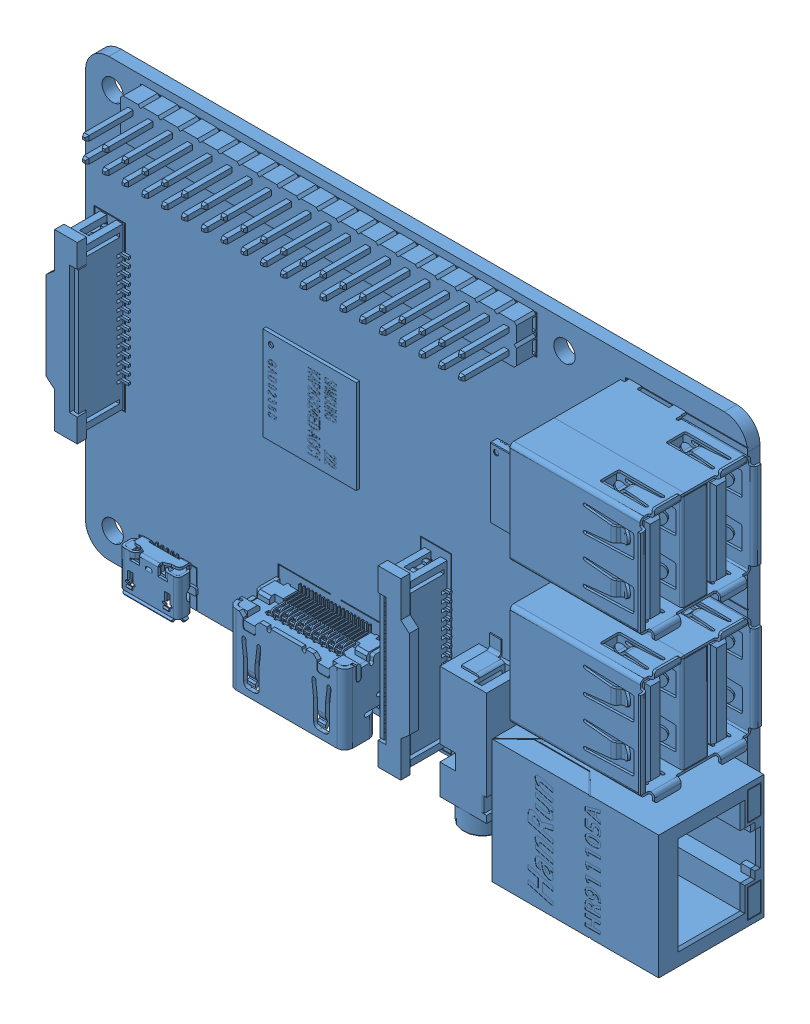
SolidWorks assembly power and control, configuration Default. Lengths in mm.
Overall size (88.51 58.54 18.92).
2 component instances, 2 part files, 4 mates.
Components (placement in the parent):
- raspberrypi_b_+_(assembly)-1: raspberrypi_b_+_(assembly) [Default] at origin size (88.51 58.54 18.92)
- board mount-1: board mount [Default] at (-155.6004 -23.5517 -7.5) x (1 0 0) z (0 -1 0) (suppressed, hidden)
Mates (geometry in assembly coordinates):
- Coincident2: coordinate: point of raspberrypi_b_+_(assembly)-1; point of assembly
- Concentric6: concentric anti-aligned: circle of raspberrypi_b_+_(assembly)-1; cylinder of board mount-1 through (-155.6004 25.4483 0) axis (0 0 -1) radius 2.5
- Concentric7: concentric aligned: cylinder of raspberrypi_b_+_(assembly)-1 through (-155.6004 -23.5517 1.6) axis (0 0 -1) radius 1.375; cylinder of board mount-1 through (-155.6004 -23.5517 0) axis (0 0 -1) radius 2.5
- Coincident10: coincident anti-aligned: plane of raspberrypi_b_+_(assembly)-1 through (-156.1004 -24.0517 0) normal (0 0 -1); plane of board mount-1 through (-155.6004 -23.5517 0) normal (0 0 1)
